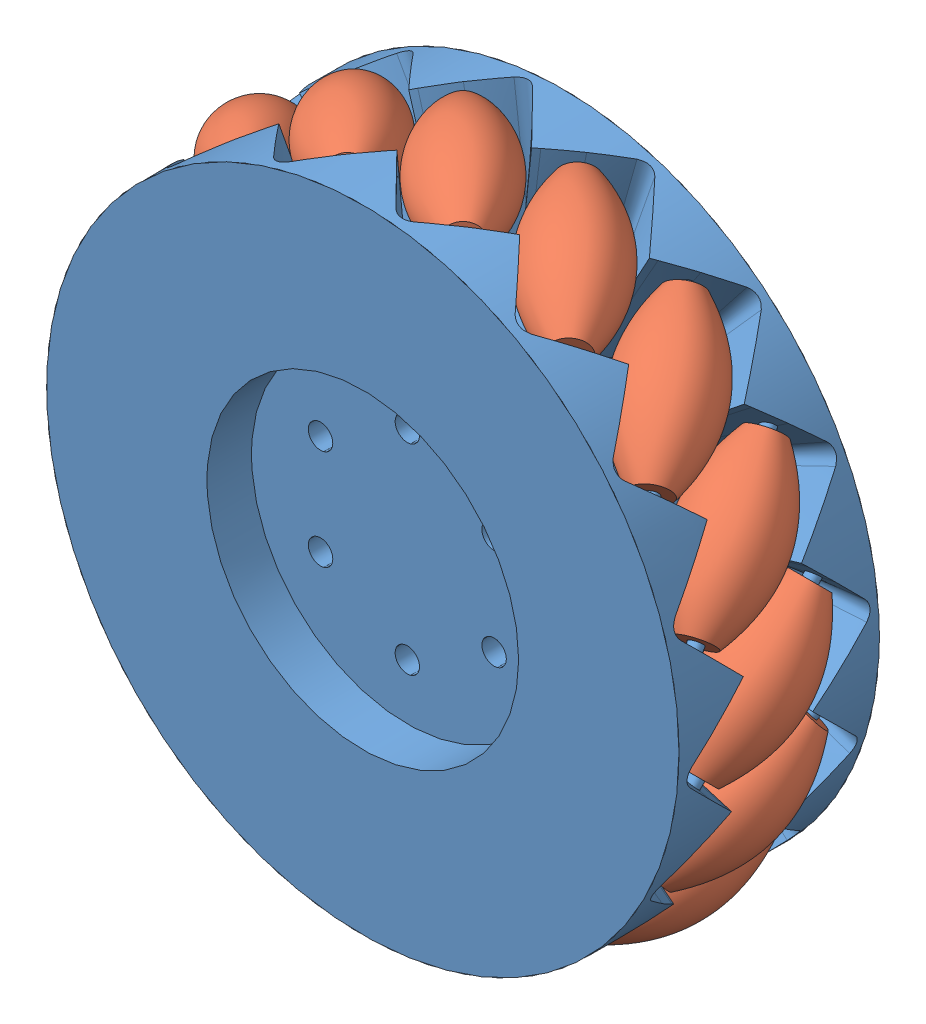
SolidWorks assembly 装配体1, configuration 默认. Lengths in mm.
Overall size (157.87 159.09 45.13).
17 component instances, 2 part files, 1 mates.
Components (placement in the parent):
- 麦克纳姆轮2-1: 麦克纳姆轮2 [默认] at (-59.988 10.803 142.3063) size (142.16 158.52 45)
- 橡胶滚子-1: 橡胶滚子 [默认] at (-4.2153 47.095 178.5812) x (0.5 -0.5 0.707107) z (-0.804446 0.034237 0.593038) size (36 20 20)
- 橡胶滚子-2: 橡胶滚子 [默认] at (-22.3491 65.6758 178.5812) x (0.653281 -0.270598 0.707107) z (-0.756313 -0.276218 0.593038) size (36 20 20)
- 橡胶滚子-3: 橡胶滚子 [默认] at (-46.2131 75.9026 178.5812) x (0.707107 0 0.707107) z (-0.593038 -0.54462 0.593038) size (36 20 20)
- 橡胶滚子-4: 橡胶滚子 [默认] at (-72.1742 76.2187 178.5812) x (0.653281 0.270598 0.707107) z (-0.339479 -0.730109 0.593038) size (36 20 20)
- 橡胶滚子-5: 橡胶滚子 [默认] at (-96.28 66.5758 178.5812) x (0.5 0.5 0.707107) z (-0.034237 -0.804446 0.593038) size (36 20 20)
- 橡胶滚子-6: 橡胶滚子 [默认] at (-114.8607 48.442 178.5812) x (0.270598 0.653281 0.707107) z (0.276218 -0.756313 0.593038) size (36 20 20)
- 橡胶滚子-7: 橡胶滚子 [默认] at (-125.0876 24.578 178.5812) x (0 0.707107 0.707107) z (0.54462 -0.593038 0.593038) size (36 20 20)
- 橡胶滚子-8: 橡胶滚子 [默认] at (-125.4036 -1.3831 178.5812) x (-0.270598 0.653281 0.707107) z (0.730109 -0.339479 0.593038) size (36 20 20)
- 橡胶滚子-9: 橡胶滚子 [默认] at (-115.7607 -25.4889 178.5812) x (-0.5 0.5 0.707107) z (0.804446 -0.034237 0.593038) size (36 20 20)
- 橡胶滚子-10: 橡胶滚子 [默认] at (-97.627 -44.0697 178.5812) x (-0.653281 0.270598 0.707107) z (0.756313 0.276218 0.593038) size (36 20 20)
- 橡胶滚子-11: 橡胶滚子 [默认] at (-73.763 -54.2965 178.5812) x (-0.707107 0 0.707107) z (0.593038 0.54462 0.593038) size (36 20 20)
- 橡胶滚子-12: 橡胶滚子 [默认] at (-47.8019 -54.6126 178.5812) x (-0.653281 -0.270598 0.707107) z (0.339479 0.730109 0.593038) size (36 20 20)
- 橡胶滚子-13: 橡胶滚子 [默认] at (-23.696 -44.9697 178.5812) x (-0.5 -0.5 0.707107) z (0.034237 0.804446 0.593038) size (36 20 20)
- 橡胶滚子-14: 橡胶滚子 [默认] at (-5.1153 -26.8359 178.5812) x (-0.270598 -0.653281 0.707107) z (-0.276218 0.756313 0.593038) size (36 20 20)
- 橡胶滚子-15: 橡胶滚子 [默认] at (5.1116 -2.9719 178.5812) x (0 -0.707107 0.707107) z (-0.54462 0.593038 0.593038) size (36 20 20)
- 橡胶滚子-16: 橡胶滚子 [默认] at (5.4276 22.9892 178.5812) x (0.270598 -0.653281 0.707107) z (-0.730109 0.339479 0.593038) size (36 20 20)
Mates (geometry in assembly coordinates):
- 同心1: concentric anti-aligned: cylinder of 麦克纳姆轮2-1 through (1.0443 41.8354 186.0195) axis (-0.5 0.5 -0.707107) radius 1.5; cylinder of 橡胶滚子-1 through (-27.5441 70.4238 145.5894) axis (0.5 -0.5 0.707107) radius 1.5
